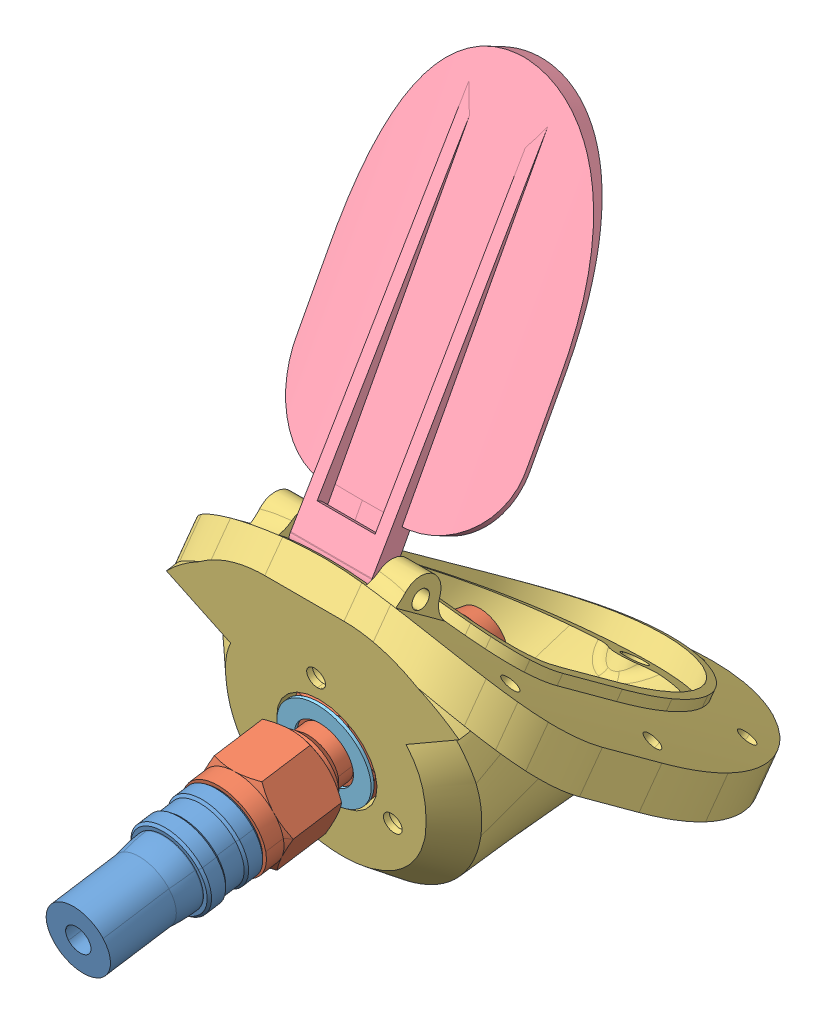
SolidWorks assembly side_clapet, configuration Défaut. Lengths in mm.
Overall size (63.65 135.28 112.81).
6 component instances, 5 part files, 0 mates.
Components (placement in the parent):
- 236100SA_FILLING_LINE_R01.CATProduct-1: 236100SA_FILLING_LINE_R01.CATProduct [Défaut] at origin size (63.65 135.28 112.81)
  - 236109_SS-TH4TA4TA4-8.CATPart-1: 236109_SS-TH4TA4TA4-8.CATPart [Défaut] at (-1.679 261.5706 -36.5068) x (0 -0.15448 0.987996) z (-0.859917 -0.504306 -0.078852) size (41.66 13.72 13.72)
  - 236106_SS-QF4-S-400.CATPart-1: 236106_SS-QF4-S-400.CATPart [Défaut] at (-1.679 259.0593 -20.4459) x (0 0.15448 -0.987996) z (0.999559 0.029342 0.004588) size (44.96 14.3 16.5)
  - 236130_QUICK_FITTING_HOLDER_R05.CATPart-1: 236130_QUICK_FITTING_HOLDER_R05.CATPart [Défaut] at (-1.679 250.22 36.0872) x (-1 0 0) z (0 0.807852 -0.589385) size (63.65 82.68 39.71)
  - 236131_COVER_R01.CATPart-1: 236131_COVER_R01.CATPart [Défaut] at (-1.9173 218.291 -89.0139) x (-1 0 0) z (0 0.470072 0.882628) size (39.54 69.43 6.01)
  - COMPRESSIVE_JOINT.CATPart-1: COMPRESSIVE_JOINT.CATPart [Défaut] at (-1.679 261.806 -38.0125) x (0 -0.15448 0.987996) z (-0.987996 0.152625 0.023864) size (0.5 16 16)
